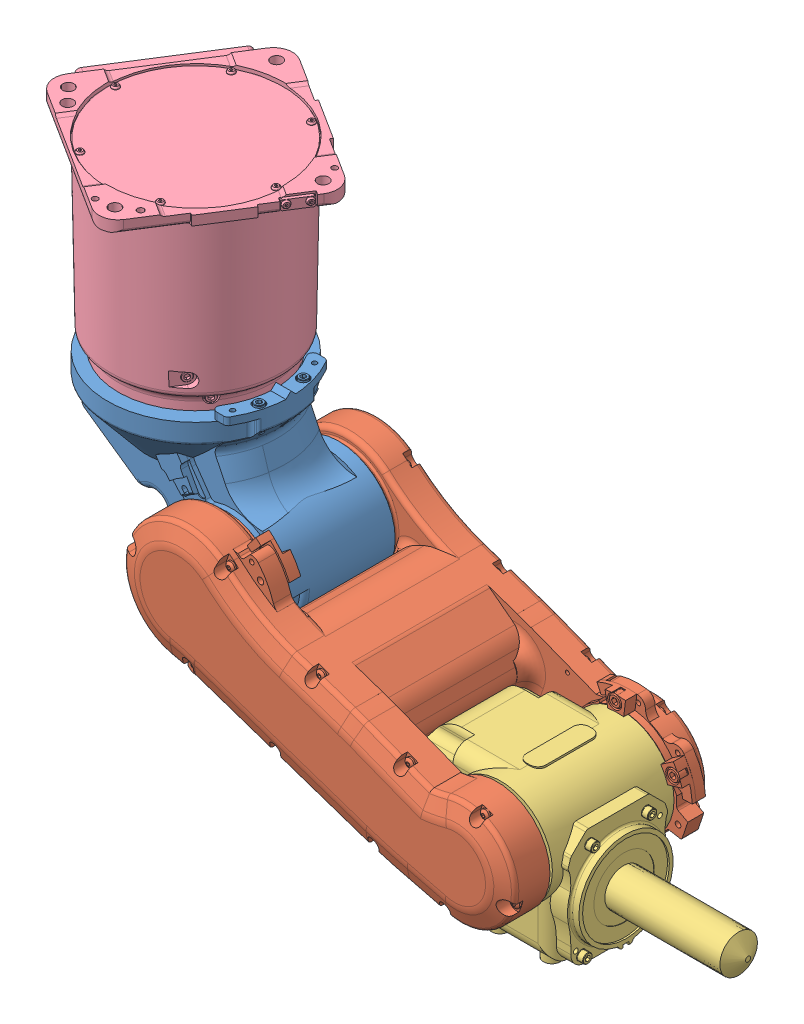
SolidWorks assembly EPSONS5, configuration Default. Lengths in mm.
Overall size (760.49 531.97 300.42).
4 component instances, 4 part files, 6 mates.
Components (placement in the parent):
- S5_ARM1-1: S5_ARM1 [Default] at (-60.7785 98.1986 288.9079) size (245.28 204.35 187)
- S5_ARM2-1: S5_ARM2 [Default] at (232.9214 -1 286.9079) x (0.947419 -0.319995 0) z (0 0 1) size (450 164.19 219.43)
- S5_ARM3-1: S5_ARM3 [Default] at (432.9214 -41 284.9079) size (300.01 155.5 134.01)
- S5_BASE-1: S5_BASE [Default] at (-148.7785 224.6986 288.9079) x (0.844223 0 0.535992) z (0 -1 0) size (250.2 197 204.01)
Mates (geometry in assembly coordinates):
- Coincident1: coincident anti-aligned: plane of S5_ARM1-1 through (-148.7785 224.6986 288.9079) normal (0 1 0); plane of S5_BASE-1 through (-148.7785 224.6986 288.9079) normal (0 -1 0)
- Concentric2: concentric aligned: cylinder of S5_ARM1-1 through (-148.7785 229.1986 288.9079) axis (0 -1 0) radius 75; cylinder of S5_BASE-1 through (-148.7785 417.1986 288.9079) axis (0 -1 0) radius 75
- Coincident2: coincident anti-aligned: plane of S5_ARM1-1 through (-60.7785 98.1986 341.9079) normal (0 0 1); plane of S5_ARM2-1 through (-13.4075 82.1988 341.9079) normal (0 0 -1)
- Concentric3: concentric anti-aligned: cone of S5_ARM1-1 through (-60.7785 98.1986 344.4079) axis (0 0 -1); cylinder of S5_ARM2-1 through (-60.7785 98.1986 341.9079) axis (0 0 1) radius 50
- Coincident3: coincident anti-aligned: plane of S5_ARM2-1 through (280.2924 -16.9997 215.9079) normal (0 0 1); plane of S5_ARM3-1 through (232.9214 -51 215.9079) normal (0 0 -1)
- Concentric4: concentric aligned: cylinder of S5_ARM2-1 through (232.9214 -1 215.9079) axis (0 0 1) radius 50; cylinder of S5_ARM3-1 through (232.9214 -1 215.9079) axis (0 0 1) radius 50
